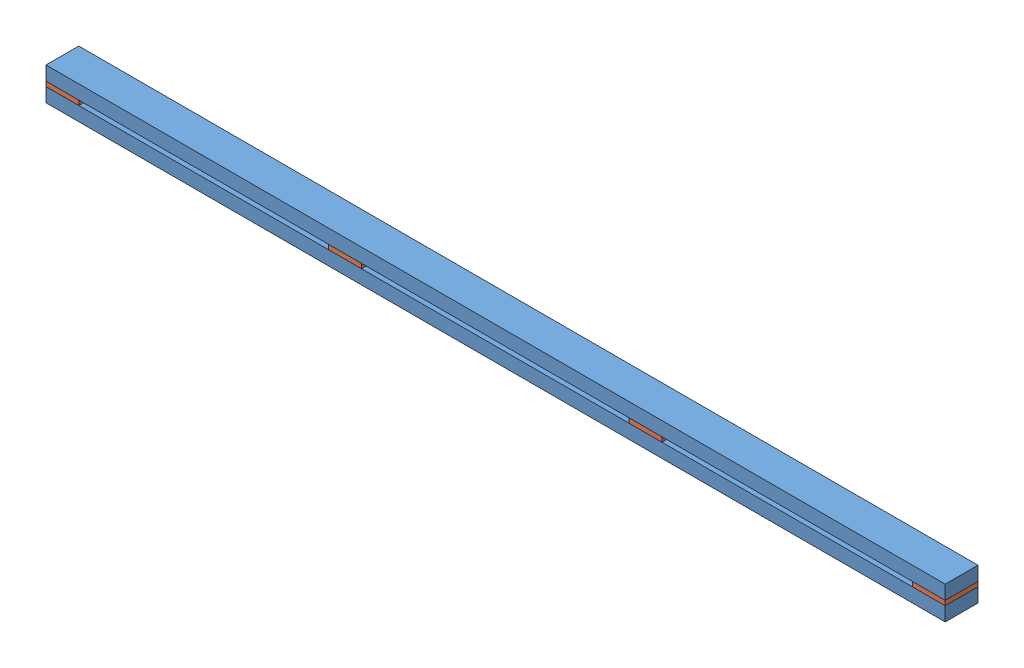
SolidWorks assembly 4x4_post, configuration Default. Lengths in mm.
Overall size (2438.4 88.9 88.9).
6 component instances, 2 part files, 14 mates.
Components (placement in the parent):
- 2x4-1: 2x4 [Default] at (89.0447 1650.5978 2048.107) size (2438.4 38.1 88.9)
- 4x4_gusset-1: 4x4_gusset [Default] at (89.0447 1688.6978 2048.107) size (88.9 12.7 88.9)
- 4x4_gusset-2: 4x4_gusset [Default] at (2438.5447 1688.6978 2048.107) size (88.9 12.7 88.9)
- 4x4_gusset-3: 4x4_gusset [Default] at (855.7374 1688.6978 2048.107) size (88.9 12.7 88.9)
- 4x4_gusset-4: 4x4_gusset [Default] at (1670.1947 1688.6978 2048.107) size (88.9 12.7 88.9)
- 2x4-2: 2x4 [Default] at (89.0447 1701.3978 2048.107) size (2438.4 38.1 88.9)
Mates (geometry in assembly coordinates):
- Coincident1: coincident: plane of 2x4-1 through (89.0447 1688.6978 2048.107) normal (-1 0 0); plane of 4x4_gusset-1 through (89.0447 1701.3978 2048.107) normal (-1 0 0)
- Coincident2: coincident: plane of 2x4-1 through (89.0447 1688.6978 2048.107) normal (0 1 0); plane of 4x4_gusset-1 through (89.0447 1688.6978 2048.107) normal (0 -1 0)
- Coincident3: coincident: plane of 2x4-1 through (89.0447 1688.6978 2137.007) normal (0 0 1); plane of 4x4_gusset-1 through (89.0447 1701.3978 2137.007) normal (0 0 1)
- Coincident4: coincident: plane of 2x4-1 through (89.0447 1688.6978 2048.107) normal (0 1 0); plane of 4x4_gusset-3 through (855.7374 1688.6978 2048.107) normal (0 -1 0)
- Coincident5: coincident: line of 2x4-1 through (89.0447 1688.6978 2137.007) axis (1 0 0); point of 4x4_gusset-3
- Coincident6: coincident: plane of 2x4-1 through (89.0447 1688.6978 2048.107) normal (0 0 -1); plane of 4x4_gusset-3 through (855.7374 1701.3978 2048.107) normal (0 0 -1)
- Coincident7: coincident: point of 2x4-1; point of 4x4_gusset-4
- Coincident8: coincident: plane of 2x4-1 through (89.0447 1688.6978 2048.107) normal (0 0 -1); plane of 4x4_gusset-4 through (1670.1947 1701.3978 2048.107) normal (0 0 -1)
- Coincident9: coincident: plane of 2x4-1 through (89.0447 1688.6978 2048.107) normal (0 1 0); plane of 4x4_gusset-2 through (2438.5447 1688.6978 2048.107) normal (0 -1 0)
- Coincident10: coincident: plane of 2x4-1 through (2527.4447 1688.6978 2048.107) normal (1 0 0); plane of 4x4_gusset-2 through (2527.4447 1701.3978 2048.107) normal (1 0 0)
- Coincident11: coincident: plane of 2x4-1 through (89.0447 1688.6978 2048.107) normal (0 0 -1); plane of 4x4_gusset-2 through (2438.5447 1701.3978 2048.107) normal (0 0 -1)
- Coincident12: coincident: plane of 4x4_gusset-2 through (2527.4447 1701.3978 2048.107) normal (1 0 0); plane of 2x4-2 through (2527.4447 1739.4978 2048.107) normal (1 0 0)
- Coincident13: coincident: plane of 4x4_gusset-2 through (2438.5447 1701.3978 2048.107) normal (0 1 0); plane of 2x4-2 through (89.0447 1701.3978 2048.107) normal (0 -1 0)
- Coincident14: coincident: plane of 2x4-1 through (89.0447 1688.6978 2137.007) normal (0 0 1); plane of 2x4-2 through (89.0447 1739.4978 2137.007) normal (0 0 1)
